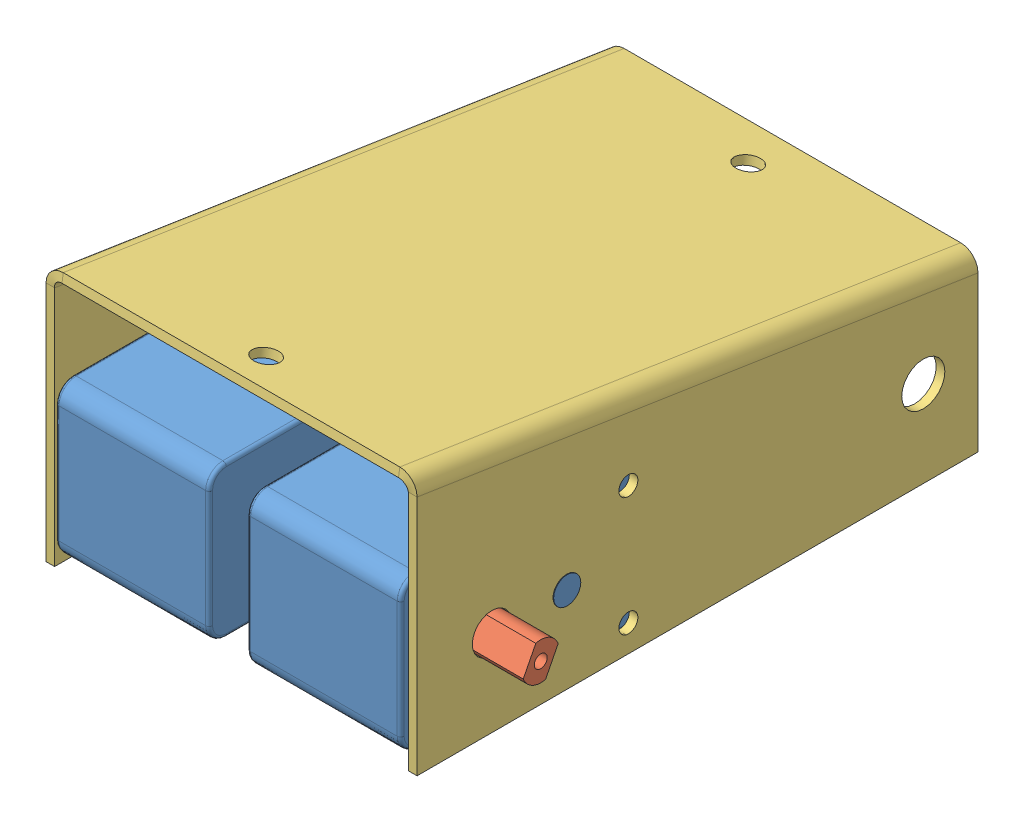
SolidWorks assembly Assem5, configuration Default. Lengths in mm.
Overall size (69 38.1 83.06).
7 component instances, 3 part files, 6 mates.
Components (placement in the parent):
- vigorprecision BO1-1: vigorprecision BO1 [Default] at (-19.8477 -5.3253 14.0913) size (31.7 22.3 64.4)
  - motor-1: motor [Default] at (-22.6 -22.3 0) size (24.6 22.3 64.4)
  - motor shaft-1: motor shaft [Default] at (-1.27 -11.15 -11.508) x (0 -0.890994 0.454014) z (1 0 0) size (5.5 3.7 10.37)
- vigorprecision BO1-2: vigorprecision BO1 [Default] at (-70.6477 -27.6253 14.0913) x (-1 0 0) z (0 0 1) size (31.7 22.3 64.4)
  - motor-1: motor [Default] at (-22.6 -22.3 0) size (24.6 22.3 64.4)
  - motor shaft-1: motor shaft [Default] at (-1.27 -11.15 -11.508) x (0 -0.890994 0.454014) z (1 0 0) size (5.5 3.7 10.37)
- framev1-1: framev1 [Default] at (-17.9427 -29.1753 -68.9667) x (-1 0 0) z (0 0 -1) size (54.61 38.1 82.74)
Mates (geometry in assembly coordinates):
- Distance1: distance = 50.8 mm anti-aligned: plane of vigorprecision BO1-2/motor-1 through (-70.6477 -5.3253 14.0913) normal (-1 0 0); plane of vigorprecision BO1-1/motor-1 through (-19.8477 -27.6253 14.0913) normal (1 0 0)
- Coincident2: coincident aligned: plane of vigorprecision BO1-1/motor-1 through (-19.8477 -5.3253 14.0913) normal (0 1 0); plane of vigorprecision BO1-2/motor-1 through (-70.6477 -5.3253 14.0913) normal (0 1 0)
- Coincident3: coincident aligned: plane of vigorprecision BO1-1/motor-1 through (-19.8477 -27.6253 14.0913) normal (0 0 1); plane of vigorprecision BO1-2/motor-1 through (-70.6477 -5.3253 14.0913) normal (0 0 1)
- Distance2: distance = 0.635 mm anti-aligned: plane of vigorprecision BO1-1/motor-1 through (-19.8477 -27.6253 14.0913) normal (1 0 0); plane of framev1-1 through (-19.2127 -29.1753 -68.9667) normal (-1 0 0)
- Concentric1: concentric aligned: cylinder of vigorprecision BO1-1/motor shaft-1 through (-10.7477 -16.4753 2.5833) axis (-1 0 0) radius 2.75; cylinder of framev1-1 through (-17.9427 -16.4753 2.5833) axis (-1 0 0) radius 2.877
- Concentric2: concentric aligned: cylinder of vigorprecision BO1-1/motor-1 through (-17.8477 -16.4753 -8.4167) axis (-1 0 0) radius 2; cylinder of framev1-1 through (-17.9427 -16.4753 -8.4167) axis (-1 0 0) radius 2
